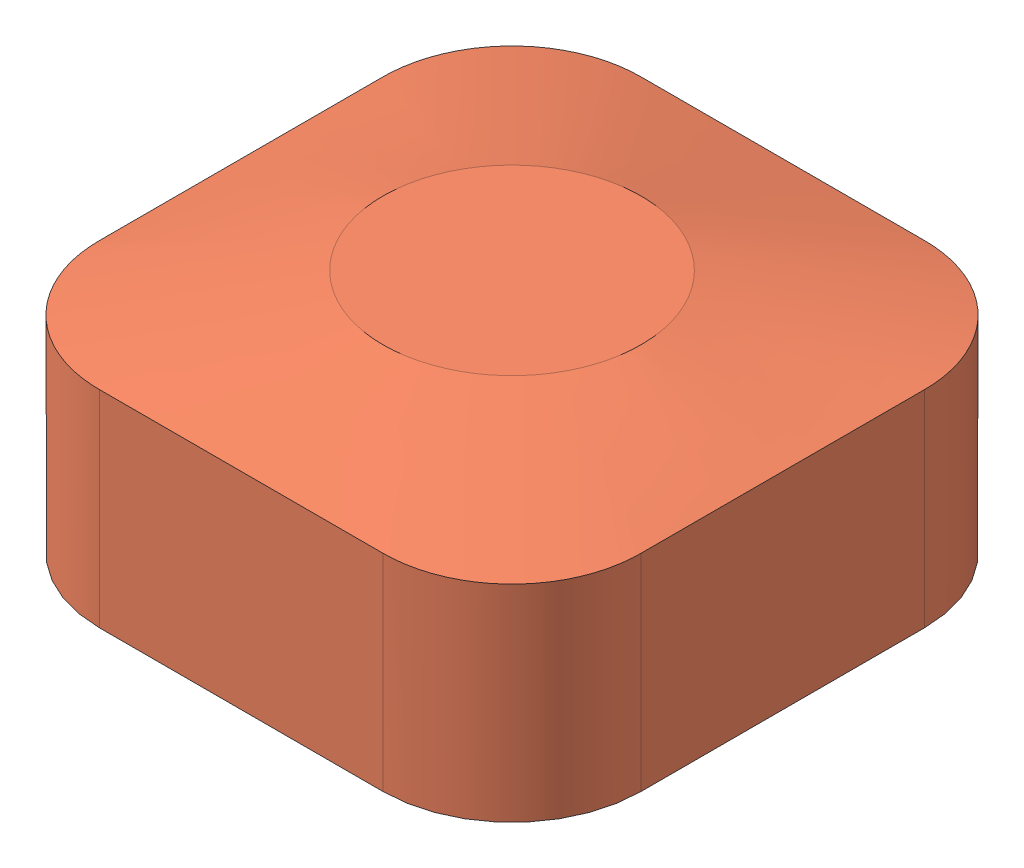
SolidWorks assembly Yellow, configuration Default. Lengths in mm.
Overall size (21 9.5 21).
2 component instances, 2 part files, 3 mates.
Components (placement in the parent):
- yellow lower-1: yellow lower [Default] at origin size (17.4 6.5 17.4)
- yellow upper-1: yellow upper [Default] at (-19.2 0 -1.8) size (21 9.5 21)
Mates (geometry in assembly coordinates):
- Width1: width anti-aligned: plane of yellow upper-1 through (-19.2 8 -1.8) normal (0 0 -1); plane of yellow upper-1 through (1.8 8 19.2) normal (0 0 1); plane of yellow lower-1 through (0 6.5 17.4) normal (0 0 1); plane of yellow lower-1 through (0 6.5 0) normal (0 0 -1)
- Width2: width anti-aligned: plane of yellow upper-1 through (1.8 8 -1.8) normal (1 0 0); plane of yellow upper-1 through (-19.2 8 19.2) normal (-1 0 0); plane of yellow lower-1 through (-17.4 6.5 0) normal (-1 0 0); plane of yellow lower-1 through (0 6.5 0) normal (1 0 0)
- Coincident1: coincident aligned: plane of yellow lower-1 through (0 0 0) normal (0 -1 0); plane of yellow upper-1 through (-19.2 0 -1.8) normal (0 -1 0)
